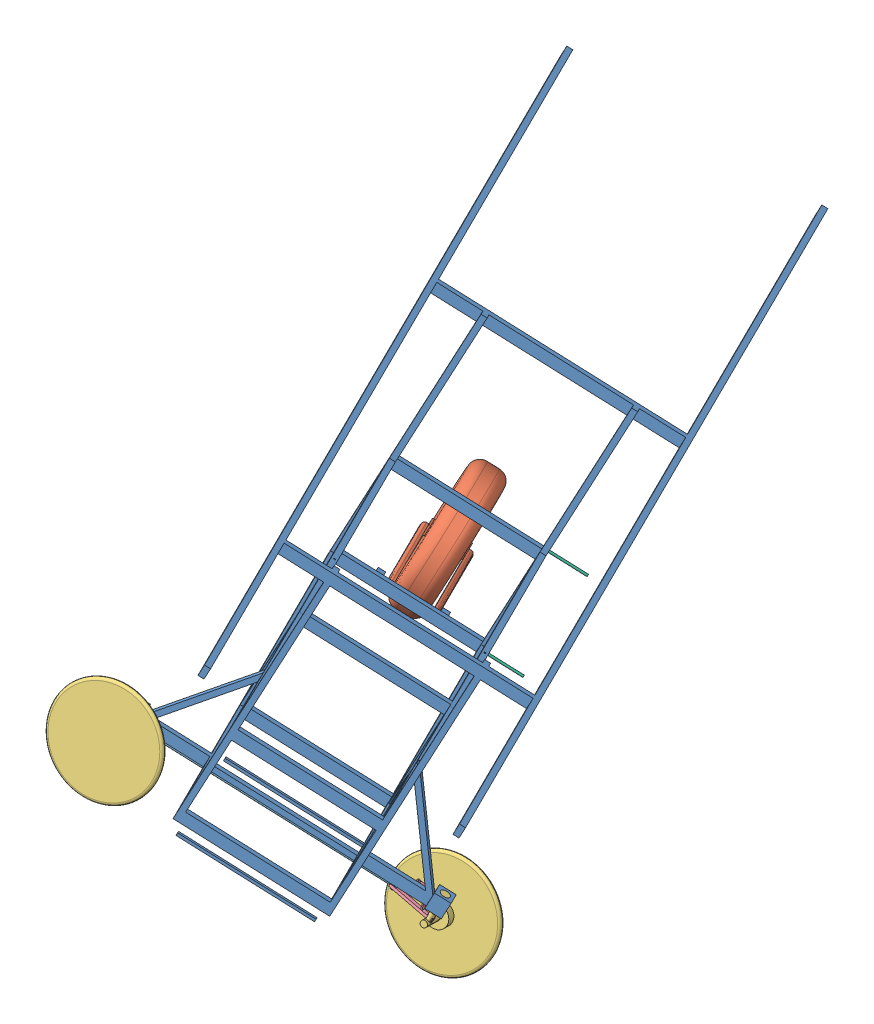
SolidWorks assembly solarcar, configuration Default. Lengths in mm.
Overall size (3961.5 2352.83 5233.26).
11 component instances, 6 part files, 23 mates.
Components (placement in the parent):
- finalDoneskies_1-1: finalDoneskies_1 [Default] at (328.0682 1149.7973 10543.5461) x (-0.493151 -0.13416 -0.859537) z (0.806318 -0.441401 -0.393722) size (5003.8 1219.2 1358.9)
- rearWheel_1-1: rearWheel_1 [Default] at (-1267.0085 945.4096 8446.8749) x (-0.493151 -0.13416 -0.859537) z (0.806318 -0.441401 -0.393722) size (793.75 622.3 241.32)
- lefttURNwHEEL_1-1: lefttURNwHEEL_1 [Default] at (60.9891 871.9381 10113.1943) x (-0.219473 0.902539 -0.37048) z (-0.97552 -0.2084 0.07021) size (677.81 299 685.22)
  - pizza wheel_1-1: pizza wheel_1 [Default] at (-55.5421 176.9459 -250.9325) x (0.849801 -0.028004 -0.526359) z (-0.168606 -0.960565 -0.221106) size (482.6 482.6 158.22)
  - steeringBracket_1-1: steeringBracket_1 [Default] at (31.3891 7.1803 -128.9838) x (-0.849801 0.028004 0.526359) z (0.49941 -0.276643 0.82101) size (93.42 20.57 203.2)
- righttURNwHEEL_1-1: righttURNwHEEL_1 [Default] at (-449.2081 1236.5022 10594.4881) x (0.774908 0.603073 -0.189263) z (0.631734 -0.729144 0.263174) size (677.81 299 685.22)
  - pizza wheel_1-1: pizza wheel_1 [Default] at (-55.5421 176.9459 -250.9325) x (0.849801 -0.028004 -0.526359) z (-0.168606 -0.960565 -0.221106) size (482.6 482.6 158.22)
  - steeringBracket_1-1: steeringBracket_1 [Default] at (-162.3551 92.8188 -446.3378) x (-0.849801 0.028004 0.526359) z (-0.49941 0.276643 -0.82101) size (93.42 20.57 203.2)
- stableBar_1-1: stableBar_1 [Default] at (191.09 938.0685 10093.125) x (0.805529 -0.441614 -0.395095) z (0.494439 0.133454 0.858906) size (1315.57 28.02 17.58)
- 6.5in cylinder-5: 6.5in cylinder [Default] at (-420.3664 1181.3215 8491.6131) x (0.074842 0.736441 -0.672349) z (0.586728 0.51266 0.626841) size (10.05 165.1 10.05)
- 6.5in cylinder-7: 6.5in cylinder [Default] at (-582.9853 739.5305 8653.8704) x (0.590798 0.633038 0.500221) z (0.028443 -0.635947 0.771208) size (10.05 165.1 10.05)
Mates (geometry in assembly coordinates):
- Coincident3: coincident: circle of finalDoneskies_1-1; circle of rearWheel_1-1
- Concentric14: concentric anti-aligned: cylinder of finalDoneskies_1-1 through (372.4617 896.8414 10055.1943) axis (0.326578 0.887224 -0.325852) radius 15.0812; cylinder of lefttURNwHEEL_1-1/pizza wheel_1-1 through (391.7893 949.3491 10035.9097) axis (-0.326578 -0.887224 0.325852) radius 13.6525
- Coincident23: coincident aligned: plane of finalDoneskies_1-1 through (408.2843 944.3465 9986.5943) normal (0.326578 0.887224 -0.325852); plane of lefttURNwHEEL_1-1/pizza wheel_1-1 through (397.347 964.4479 10030.3644) normal (0.326578 0.887224 -0.325852)
- Coincident24: coincident anti-aligned: plane of lefttURNwHEEL_1-1/steeringBracket_1-1 through (189.0989 940.9744 10100.9903) normal (0.326578 0.887224 -0.325852); plane of stableBar_1-1 through (190.8826 937.5051 10093.332) normal (-0.326578 -0.887224 0.325852)
- Concentric23: concentric anti-aligned: cylinder of lefttURNwHEEL_1-1/steeringBracket_1-1 through (191.6123 915.4386 10096.3405) axis (0.326578 0.887224 -0.325852) radius 6.35; cylinder of stableBar_1-1 through (204.4697 950.3686 10083.5117) axis (-0.326578 -0.887224 0.325852) radius 6.35
- Coincident25: coincident aligned: plane of finalDoneskies_1-1 through (-652.9745 1553.5367 10581.6617) normal (0.326578 0.887224 -0.325852); plane of righttURNwHEEL_1-1/pizza wheel_1-1 through (-642.0372 1533.4352 10537.8916) normal (0.326578 0.887224 -0.325852)
- Concentric24: concentric anti-aligned: cylinder of finalDoneskies_1-1 through (-683.5126 1420.7578 10579.2749) axis (0.326578 0.887224 -0.325852) radius 10.3187; cylinder of righttURNwHEEL_1-1/pizza wheel_1-1 through (-647.5949 1518.3365 10543.437) axis (-0.326578 -0.887224 0.325852) radius 13.6525
- Coincident26: coincident anti-aligned: plane of righttURNwHEEL_1-1/steeringBracket_1-1 through (-849.6078 1510.4977 10610.6558) normal (0.326578 0.887224 -0.325852); plane of stableBar_1-1 through (190.8826 937.5051 10093.332) normal (-0.326578 -0.887224 0.325852)
- Concentric25: concentric aligned: cylinder of righttURNwHEEL_1-1/steeringBracket_1-1 through (-847.2455 1484.9709 10605.879) axis (0.326578 0.887224 -0.325852) radius 6.35; cylinder of stableBar_1-1 through (-840.1947 1504.126 10598.8439) axis (0.326578 0.887224 -0.325852) radius 6.35
- Coincident37: coincident: plane of finalDoneskies_1-1 through (-724.1189 863.5545 8709.6387) normal (-0.493151 -0.13416 -0.859537); line of rearWheel_1-1 through (-1044.1357 991.3567 8873.2975) axis (0.326578 0.887224 -0.325852)
- Concentric27: concentric: cylinder of finalDoneskies_1-1 through (-1079.7364 1023.4542 8866.55) axis (-0.806318 0.441401 0.393722) radius 8.128; cylinder of rearWheel_1-1 through (-1076.3298 1021.5894 8864.8866) axis (0.806318 -0.441401 -0.393722) radius 8.128
- Coincident40: coincident: circle of finalDoneskies_1-1; circle of rearWheel_1-1
- Coincident41: coincident: plane of finalDoneskies_1-1 through (-1100.4723 1006.7998 8858.8835) normal (0.806318 -0.441401 -0.393722); circle of rearWheel_1-1
- Coincident42: coincident: plane of finalDoneskies_1-1 through (-893.4652 934.0931 8751.4634) normal (-0.806318 0.441401 0.393722); circle of rearWheel_1-1
- Parallel33: parallel aligned: plane of finalDoneskies_1-1 through (348.5486 1138.5857 10533.5456) normal (0.806318 -0.441401 -0.393722); plane of 6.5in cylinder-5 through (-420.3664 1181.3215 8491.6131) normal (0.806318 -0.441401 -0.393722)
- Tangent8: tangent: line of finalDoneskies_1-1 through (-720.2286 807.272 8716.1914) axis (0.326578 0.887224 -0.325852); cylinder of 6.5in cylinder-5 through (-553.4895 1254.1967 8556.6166) axis (0.806318 -0.441401 -0.393722) radius 5.0263
- Tangent11: tangent: line of finalDoneskies_1-1 through (-554.3268 1257.9819 8550.6585) axis (0.493151 0.13416 0.859537); cylinder of 6.5in cylinder-5 through (-553.4895 1254.1967 8556.6166) axis (0.806318 -0.441401 -0.393722) radius 5.0263
- Tangent13: tangent: line of finalDoneskies_1-1 through (-720.2286 807.272 8716.1914) axis (0.326578 0.887224 -0.325852); cylinder of 6.5in cylinder-5 through (-553.4895 1254.1967 8556.6166) axis (0.806318 -0.441401 -0.393722) radius 5.0263
- Coincident83: coincident anti-aligned: plane of finalDoneskies_1-1 through (348.5486 1138.5857 10533.5456) normal (0.806318 -0.441401 -0.393722); plane of 6.5in cylinder-5 through (-553.4895 1254.1967 8556.6166) normal (-0.806318 0.441401 0.393722)
- Parallel49: parallel anti-aligned: plane of finalDoneskies_1-1 through (348.5486 1138.5857 10533.5456) normal (0.806318 -0.441401 -0.393722); plane of 6.5in cylinder-7 through (-716.1084 812.4058 8718.8739) normal (-0.806318 0.441401 0.393722)
- Coincident104: coincident anti-aligned: plane of finalDoneskies_1-1 through (348.5486 1138.5857 10533.5456) normal (0.806318 -0.441401 -0.393722); plane of 6.5in cylinder-7 through (-716.1084 812.4058 8718.8739) normal (-0.806318 0.441401 0.393722)
- Tangent23: tangent: line of finalDoneskies_1-1 through (-720.2286 807.272 8716.1914) axis (0.326578 0.887224 -0.325852); cylinder of 6.5in cylinder-7 through (-716.1084 812.4058 8718.8739) axis (0.806318 -0.441401 -0.393722) radius 5.0263
- Tangent24: tangent: line of finalDoneskies_1-1 through (112.7528 1033.8808 10168.0348) axis (-0.493151 -0.13416 -0.859537); cylinder of 6.5in cylinder-7 through (-716.1084 812.4058 8718.8739) axis (0.806318 -0.441401 -0.393722) radius 5.0263
